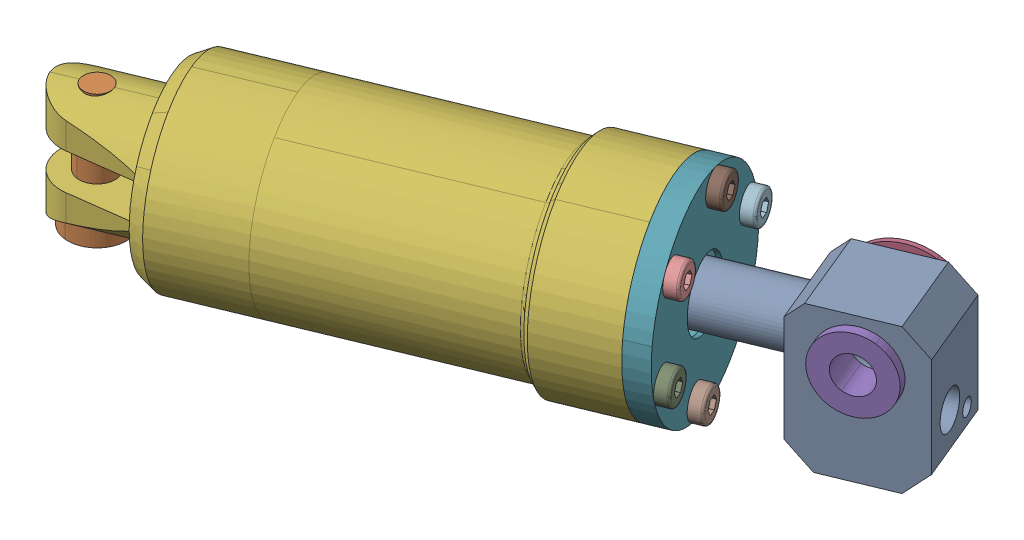
SolidWorks assembly Sub_cy2, configuration Default. Lengths in mm.
Overall size (154.53 44.01 88.72).
2 component instances, 2 part files, 2 mates.
Components (placement in the parent):
- VERIN_EPAULE_TIGE_GROUPE2.3_AllCATPart-1: VERIN_EPAULE_TIGE_GROUPE2.3_AllCATPart [Default] at (27.3021 43.4991 13.4361) x (-0.92388 0 0.382683) z (-0.382683 0 -0.92388) size (122.51 33.51 22)
- EPAULE-CYLINDRE-GROUPE2_AllCATPart-1: EPAULE-CYLINDRE-GROUPE2_AllCATPart [Default] at (-64.1566 51.0808 51.3195) x (0.92388 0 -0.382683) z (0.382683 0 0.92388) size (113.86 44 44)
Mates (geometry in assembly coordinates):
- LimitDistance1: limit distance = 4.8225 mm anti-aligned: plane of VERIN_EPAULE_TIGE_GROUPE2.3_AllCATPart-1 through (-25.5148 43.4991 35.3136) normal (-0.92388 0 0.382683); plane of EPAULE-CYLINDRE-GROUPE2_AllCATPart-1 through (-29.9702 58.4991 37.1591) normal (0.92388 0 -0.382683)
- Concentric1: concentric aligned: cylinder of VERIN_EPAULE_TIGE_GROUPE2.3_AllCATPart-1 through (20.6792 43.4991 16.1794) axis (-0.92388 0 0.382683) radius 6; cylinder of EPAULE-CYLINDRE-GROUPE2_AllCATPart-1 through (43.0163 43.4991 6.9271) axis (-0.92388 0 0.382683) radius 6
